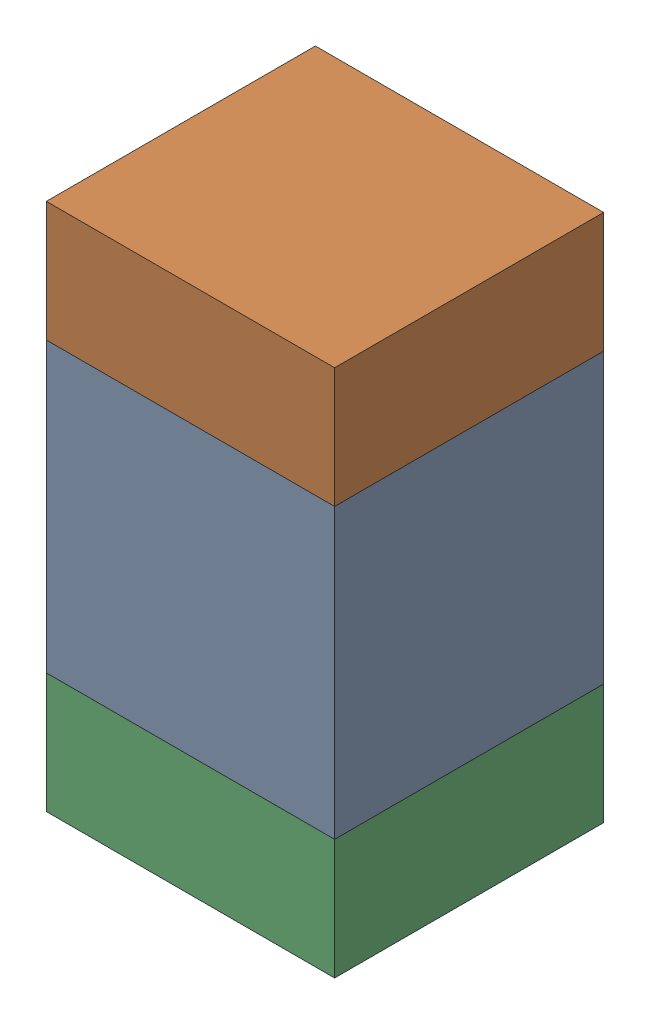
SolidWorks assembly C7, configuration Default. Lengths in mm.
Overall size (0.6 1.1 0.56).
6 component instances, 2 part files, 0 mates.
Components (placement in the parent):
- 5613967728-1: 5613967728 [Default] at (144.25 66.25 -2.2514) size (0.6 0.6 0.56)
  - Extruded-1: Extruded [Default] at origin size (0.6 0.6 0.56)
- 8144647408-1: 8144647408 [Default] at (144.25 66.675 -2.2514) size (0.6 0.25 0.56)
  - Extruded_7-1: Extruded_7 [Default] at origin size (0.6 0.25 0.56)
- 8144647408-2: 8144647408 [Default] at (144.25 65.825 -2.2514) size (0.6 0.25 0.56)
  - Extruded_7-1: Extruded_7 [Default] at origin size (0.6 0.25 0.56)
